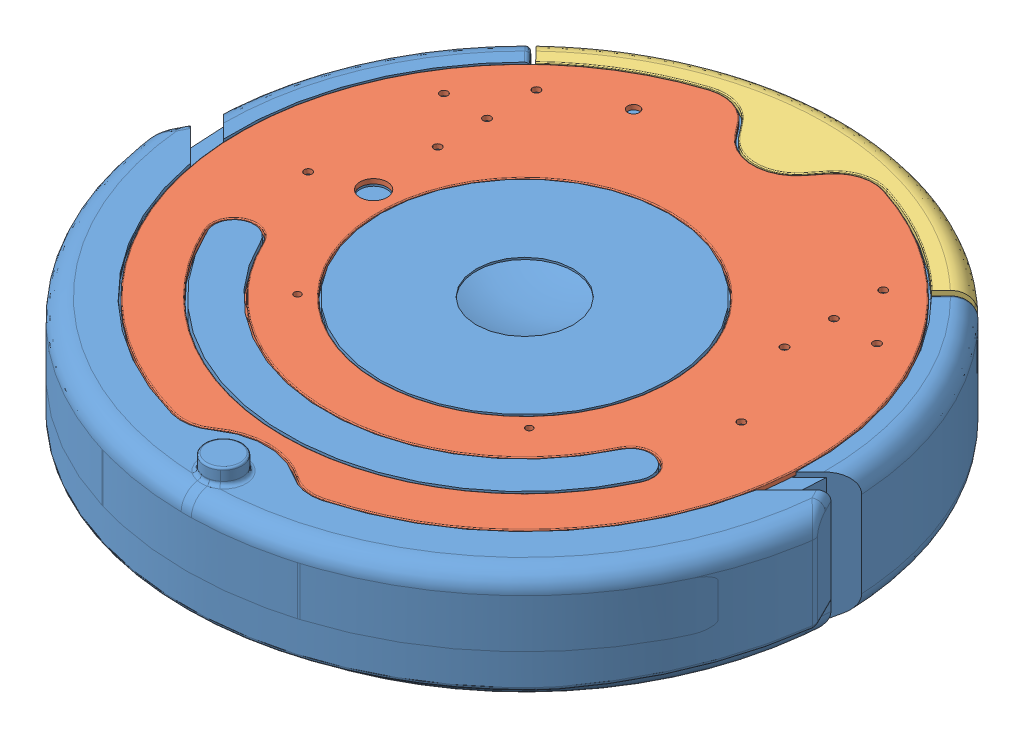
SolidWorks assembly iRobot_iCreate, configuration Default. Lengths in mm.
Overall size (347 90.95 348.54).
14 component instances, 4 part files, 38 mates.
Components (placement in the parent):
- iRobot_Create2-1: iRobot_Create2 [Default] at origin size (347 90.95 316.21)
- iRobot_Create2_Top_Plate-1: iRobot_Create2_Top_Plate [Default] at (0 80.53 0) size (294 17.6 283.51)
- c2binbottomwithoutcaster-1: c2binbottomwithoutcaster [Default] at (0 39.62 -0.0354) size (228.43 72.9 154.26)
- socket button head cap screw_ai-30: socket button head cap screw_ai [SBHCSCREW 0.125-44x0.3125-HX-S] at (0 80.4792 -82.8867) x (0 -1 0) z (0 0 1) size (9.61 6.05 6.05)
- socket button head cap screw_ai-26: socket button head cap screw_ai [SBHCSCREW 0.125-44x0.3125-HX-S] at (-109 80.4792 87.5032) x (0 -1 0) z (0.89847 0 -0.439034) size (9.61 6.05 6.05)
- socket button head cap screw_ai-23: socket button head cap screw_ai [SBHCSCREW 0.125-44x0.3125-HX-S] at (109 80.4792 87.5032) x (0 -1 0) z (0 0 1) size (9.61 6.05 6.05)
- socket button head cap screw_ai-32: socket button head cap screw_ai [SBHCSCREW 0.125-44x0.3125-HX-S] at (52 80.4792 -67.3613) x (0 -1 0) z (-0.810041 0 -0.586374) size (9.61 6.05 6.05)
- socket button head cap screw_ai-31: socket button head cap screw_ai [SBHCSCREW 0.125-44x0.3125-HX-S] at (113.5 80.4792 -78.4968) x (0 -1 0) z (-0.873172 0 -0.487412) size (9.61 6.05 6.05)
- socket button head cap screw_ai-29: socket button head cap screw_ai [SBHCSCREW 0.125-44x0.3125-HX-S] at (-52 80.4792 -67.3613) x (0 -1 0) z (-0.01327 0 -0.999912) size (9.61 6.05 6.05)
- socket button head cap screw_ai-28: socket button head cap screw_ai [SBHCSCREW 0.125-44x0.3125-HX-S] at (-113.5 80.4792 -78.4968) x (0 -1 0) z (-0.60747 0 0.794343) size (9.61 6.05 6.05)
- socket button head cap screw_ai-27: socket button head cap screw_ai [SBHCSCREW 0.125-44x0.3125-HX-S] at (-76.25 80.4792 49.1803) x (0 -1 0) z (-0.99375 0 -0.11163) size (9.61 6.05 6.05)
- socket button head cap screw_ai-25: socket button head cap screw_ai [SBHCSCREW 0.125-44x0.3125-HX-S] at (-30.22 80.4792 125.3527) x (0 -1 0) z (-0.199183 0 -0.979962) size (9.61 6.05 6.05)
- socket button head cap screw_ai-24: socket button head cap screw_ai [SBHCSCREW 0.125-44x0.3125-HX-S] at (30.22 80.4792 125.3527) x (0 -1 0) z (0.734126 0 0.679013) size (9.61 6.05 6.05)
- socket button head cap screw_ai-22: socket button head cap screw_ai [SBHCSCREW 0.125-44x0.3125-HX-S] at (76.25 80.4792 49.1803) x (0 -1 0) z (0.153576 0 -0.988137) size (9.61 6.05 6.05)
Mates (geometry in assembly coordinates):
- Concentric1: concentric aligned: cylinder of iRobot_Create2-1 through (0 0 0) axis (0 1 0) radius 170; cylinder of ? through (0 -479.8326 0) axis (0 1 0) radius 170
- Coincident3: coincident aligned: plane of iRobot_Create2-1 through (0 55 0) normal (0 1 0); plane of ? through (0 55 0) normal (0 1 0)
- Parallel1: parallel anti-aligned: plane of ? through (0 55 0) normal (-1 0 0); plane of assembly through (0 0 0) normal (1 0 0)
- Coincident4: coincident aligned: plane of iRobot_Create2-1 through (0 0 0) normal (0 0 1); plane of assembly through (0 0 0) normal (0 0 1)
- Coincident5: coincident aligned: plane of iRobot_Create2-1 through (0 0 0) normal (0 1 0); plane of assembly through (0 0 0) normal (0 1 0)
- Coincident6: coincident aligned: plane of iRobot_Create2-1 through (0 0 0) normal (1 0 0); plane of assembly through (0 0 0) normal (1 0 0)
- Coincident29: coincident anti-aligned: plane of assembly through (0 0 0) normal (1 0 0); plane of ? through (0 33.5947 49.5758) normal (-1 0 0)
- Coincident30: coincident aligned: plane of iRobot_Create2-1 through (0 0 0) normal (0 0 1); plane of assembly through (0 0 0) normal (0 0 1)
- Coincident31: coincident aligned: plane of iRobot_Create2-1 through (0 0 0) normal (0 1 0); plane of assembly through (0 0 0) normal (0 1 0)
- Coincident32: coincident aligned: plane of iRobot_Create2-1 through (0 0 0) normal (1 0 0); plane of assembly through (0 0 0) normal (1 0 0)
- Coincident33: coincident aligned: plane of iRobot_Create2_Top_Plate-1 through (0 80.53 0) normal (0 0 1); plane of assembly through (0 0 0) normal (0 0 1)
- Coincident34: coincident aligned: plane of iRobot_Create2_Top_Plate-1 through (0 80.53 0) normal (1 0 0); plane of assembly through (0 0 0) normal (1 0 0)
- Coincident35: coincident aligned: plane of iRobot_Create2-1 through (0 82.95 0) normal (0 1 0); plane of iRobot_Create2_Top_Plate-1 through (0 82.95 0) normal (0 1 0)
- Coincident36: coincident aligned: plane of c2binbottomwithoutcaster-1 through (0 39.62 -0.0354) normal (1 0 0); plane of assembly through (0 0 0) normal (1 0 0)
- Coincident37: coincident aligned: plane of iRobot_Create2-1 through (0 10.62 0) normal (0 -1 0); plane of c2binbottomwithoutcaster-1 through (0 10.62 -0.0354) normal (0 -1 0)
- Coincident49: coincident anti-aligned: plane of iRobot_Create2-1 through (53.6319 78.8028 -67.3613) normal (0 1 0); plane of socket button head cap screw_ai-32 through (51.0691 78.8028 -66.0753) normal (0 -1 0)
- Concentric13: concentric aligned: circle of iRobot_Create2-1; circle of socket button head cap screw_ai-32
- Coincident50: coincident anti-aligned: plane of iRobot_Create2-1 through (115.132 78.8028 -78.4968) normal (0 1 0); plane of socket button head cap screw_ai-31 through (112.7262 78.8028 -77.1107) normal (0 -1 0)
- Concentric14: concentric aligned: circle of iRobot_Create2-1; circle of socket button head cap screw_ai-31
- Coincident52: coincident anti-aligned: plane of iRobot_Create2-1 through (-50.368 78.8028 -67.3613) normal (0 1 0); plane of socket button head cap screw_ai-29 through (-53.5874 78.8028 -67.3402) normal (0 -1 0)
- Concentric16: concentric aligned: circle of iRobot_Create2-1; circle of socket button head cap screw_ai-29
- Concentric17: concentric aligned: circle of iRobot_Create2-1; circle of socket button head cap screw_ai-28
- Coincident54: coincident anti-aligned: plane of iRobot_Create2-1 through (-111.868 78.8028 -78.4968) normal (0 1 0); plane of socket button head cap screw_ai-28 through (-112.239 78.8028 -77.5325) normal (0 -1 0)
- Concentric18: concentric aligned: circle of iRobot_Create2-1; circle of socket button head cap screw_ai-27
- Coincident55: coincident anti-aligned: plane of iRobot_Create2-1 through (-74.6181 78.8028 49.1803) normal (0 1 0); plane of socket button head cap screw_ai-27 through (-76.4272 78.8028 50.7578) normal (0 -1 0)
- Concentric20: concentric aligned: circle of iRobot_Create2-1; circle of socket button head cap screw_ai-25
- Coincident57: coincident anti-aligned: plane of iRobot_Create2-1 through (-28.588 78.8028 125.3527) normal (0 1 0); plane of socket button head cap screw_ai-25 through (-31.7757 78.8028 125.6689) normal (0 -1 0)
- Concentric21: concentric aligned: circle of iRobot_Create2-1; circle of socket button head cap screw_ai-24
- Coincident58: coincident anti-aligned: plane of iRobot_Create2-1 through (31.8519 78.8028 125.3527) normal (0 1 0); plane of socket button head cap screw_ai-24 through (31.2979 78.8028 124.1873) normal (0 -1 0)
- Concentric23: concentric aligned: circle of iRobot_Create2-1; circle of socket button head cap screw_ai-22
- Coincident60: coincident anti-aligned: plane of iRobot_Create2-1 through (77.882 78.8028 49.1803) normal (0 1 0); plane of socket button head cap screw_ai-22 through (74.6813 78.8028 48.9365) normal (0 -1 0)
- Concentric24: concentric aligned: circle of iRobot_Create2-1; circle of socket button head cap screw_ai-23
- Concentric25: concentric aligned: circle of iRobot_Create2-1; circle of socket button head cap screw_ai-26
- Concentric26: concentric aligned: circle of iRobot_Create2-1; circle of socket button head cap screw_ai-30
- Coincident62: coincident aligned: plane of socket button head cap screw_ai-30 through (1.5875 78.8028 -82.8867) normal (0 -1 0); plane of socket button head cap screw_ai-26 through (-109.697 78.8028 86.0769) normal (0 -1 0)
- Coincident63: coincident aligned: plane of socket button head cap screw_ai-30 through (1.5875 78.8028 -82.8867) normal (0 -1 0); plane of socket button head cap screw_ai-23 through (110.5875 78.8028 87.5032) normal (0 -1 0)
- Coincident64: coincident aligned: plane of socket button head cap screw_ai-24 through (31.2979 78.8028 124.1873) normal (0 -1 0); plane of socket button head cap screw_ai-23 through (110.5875 78.8028 87.5032) normal (0 -1 0)
- Coincident65: coincident anti-aligned: plane of iRobot_Create2-1 through (1.632 78.8028 -82.8867) normal (0 1 0); plane of socket button head cap screw_ai-30 through (1.5875 78.8028 -82.8867) normal (0 -1 0)
